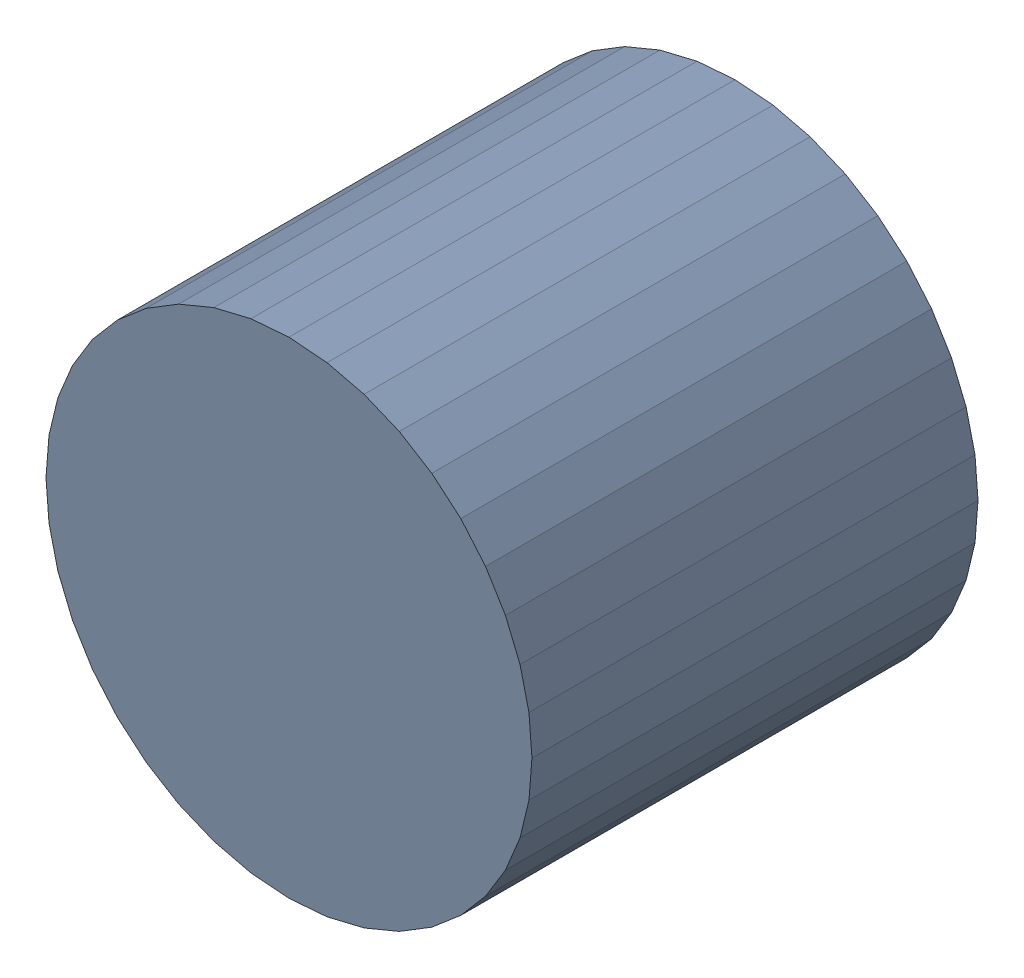
SolidWorks assembly C10_0Kanaloa_v2.0.0_Motor, configuration Default. Lengths in mm.
Overall size (6.32 6.32 5.8).
2 component instances, 1 part files, 0 mates.
Components (placement in the parent):
- 352892112-1: 352892112 [Default] at (46.212 44.45 0) size (6.32 6.32 5.8)
  - Extruded_11-1: Extruded_11 [Default] at origin size (6.32 6.32 5.8)
